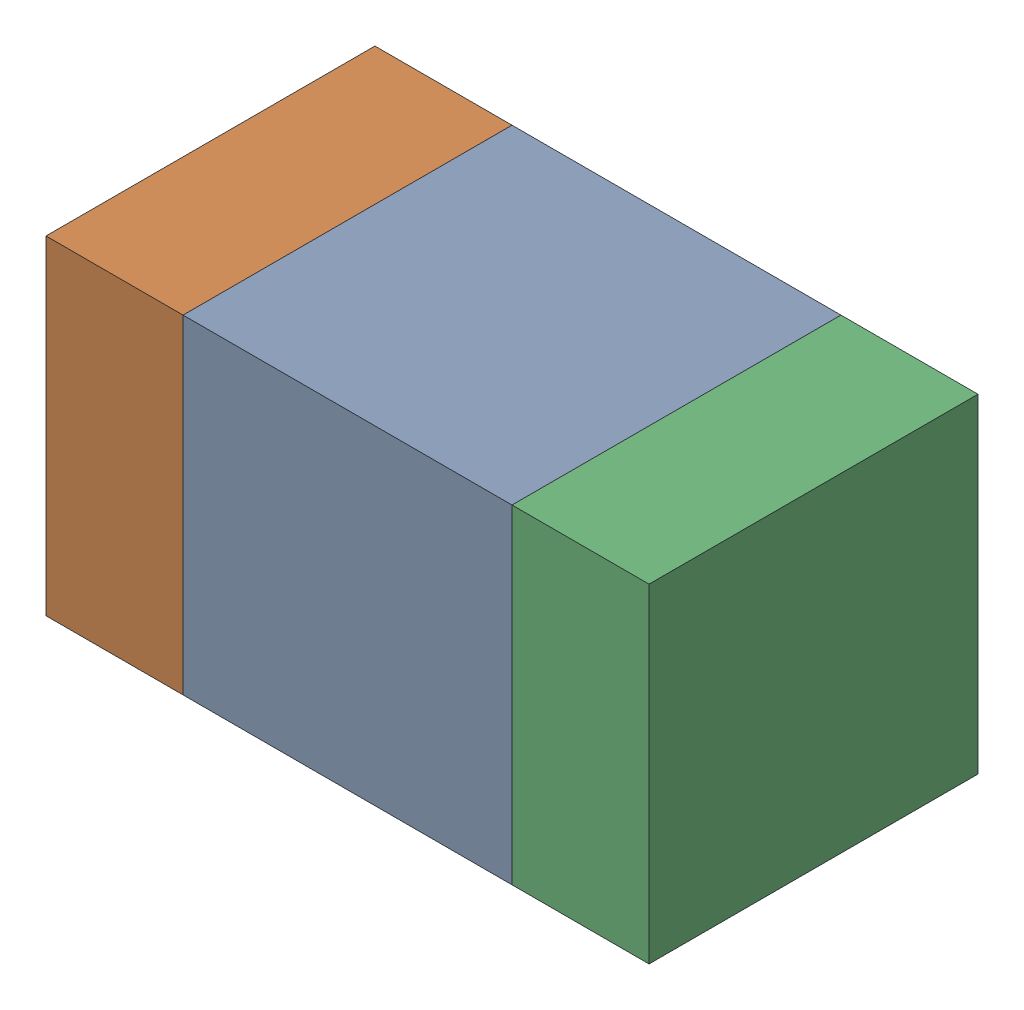
SolidWorks assembly C424PCB, configuration Default. Lengths in mm.
Overall size (1.1 0.6 0.6).
6 component instances, 2 part files, 0 mates.
Components (placement in the parent):
- 761606048-1: 761606048 [Default] at (116.7 102.4 -2.2638) size (0.6 0.6 0.6)
  - Extruded_9-1: Extruded_9 [Default] at origin size (0.6 0.6 0.6)
- 854785160-1: 854785160 [Default] at (116.275 102.4 -2.2638) size (0.25 0.6 0.6)
  - Extruded_19-1: Extruded_19 [Default] at origin size (0.25 0.6 0.6)
- 854785160-2: 854785160 [Default] at (117.125 102.4 -2.2638) size (0.25 0.6 0.6)
  - Extruded_19-1: Extruded_19 [Default] at origin size (0.25 0.6 0.6)
